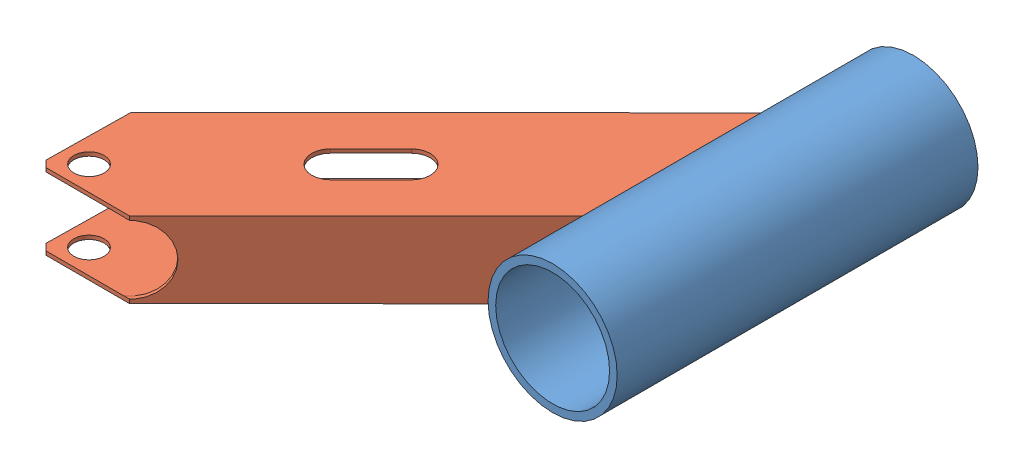
SolidWorks assembly Assemblage2, configuration Défaut. Lengths in mm.
Overall size (114.24 34 132.89).
2 component instances, 2 part files, 2 mates.
Components (placement in the parent):
- tube moyeu-1: tube moyeu [Default] at (13.2241 2.8275 -4.8974) size (34 34 95)
- equerre-1: equerre [Default] at (-13.7937 -29.8863 -4.6452) x (1 -0.000928 0) z (-0.000928 -1 0) size (83.49 106.89 20)
Mates (geometry in assembly coordinates):
- Coaxiale1: concentric anti-aligned: cylinder of tube moyeu-1 through (13.2241 2.8275 42.6026) axis (0 0 -1) radius 17; cylinder of equerre-1 through (13.2241 2.8275 -32.742) axis (0 0 1) radius 17
- Distance1: distance = 26 mm: plane of tube moyeu-1 through (13.2241 2.8275 -52.3974) normal (0 0 -1); point of equerre-1
